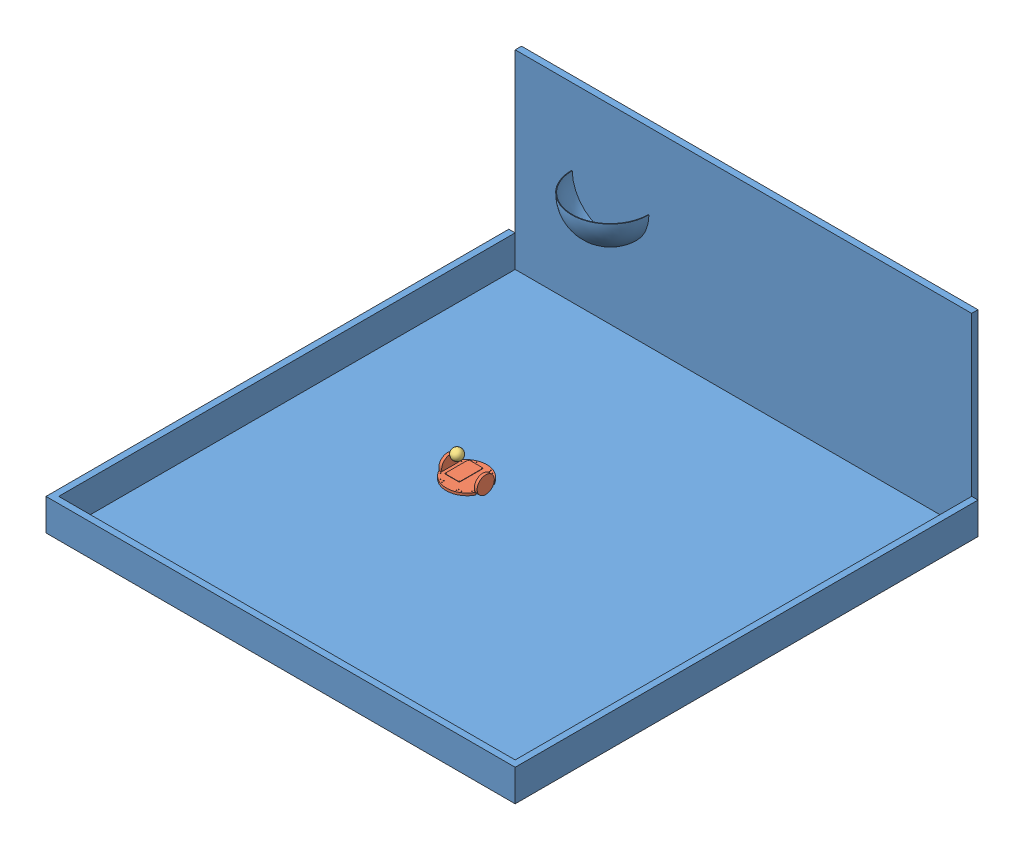
SolidWorks assembly mechatronics_project_assembly, configuration Default. Lengths in mm.
Overall size (1879.6 787.4 1879.6).
3 component instances, 3 part files, 0 mates.
Components (placement in the parent):
- basketball_court-1: basketball_court [Default] at (-553.2872 642.2457 2335.0048) size (1879.6 787.4 1879.6)
- RSLKRobot-1: RSLKRobot [Default] at (51.9314 717.5567 1417.0009) size (153.54 68.83 162.51)
- ball-1: ball [Default] at (119.5568 816.0386 1411.711) size (42.67 42.67 42.67)
